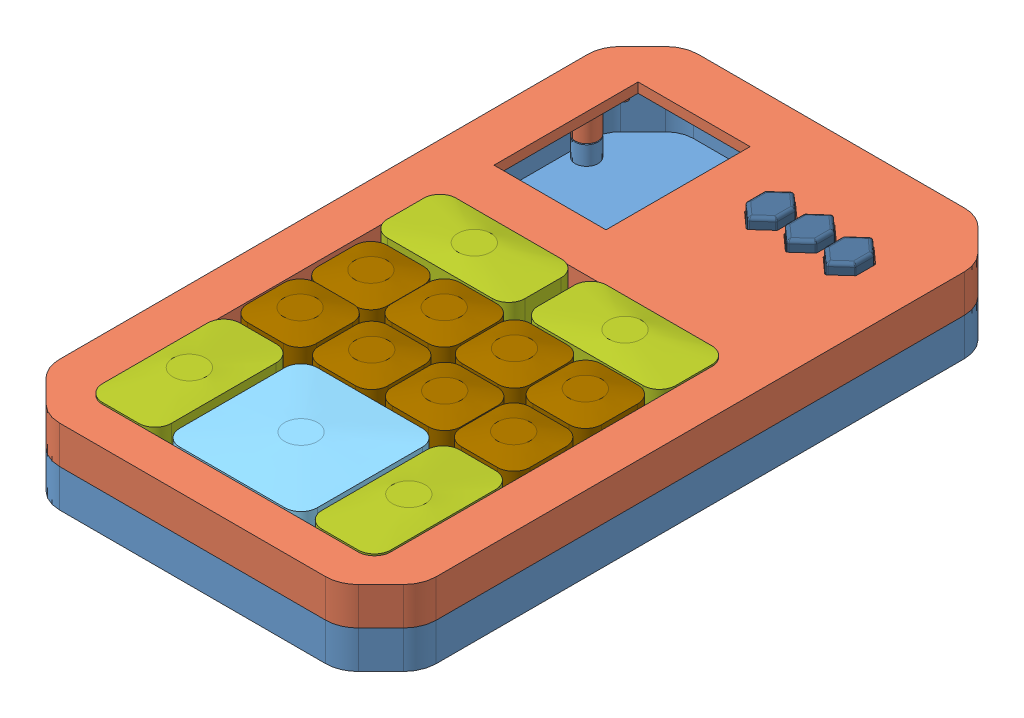
SolidWorks assembly assembly final, configuration Default. Lengths in mm.
Overall size (115 26 195).
46 component instances, 11 part files, 40 mates.
Components (placement in the parent):
- Lower Part-1: Lower Part [Default] at origin size (115 14.5 195)
- PCB board-1: PCB board [Default] at (57.5 10.5 83.7721) size (88 7.5 175) (hidden)
- Upper Part-1: Upper Part [Default] at (0 3 0) size (115 15.5 195)
- batterycap-1: batterycap [Default] at (53.4 1.5 23.6721) x (-1 0 0) z (0 0 1) size (50.2 3 48.69)
- RED-1: RED [Default] at (77.2998 15.5 130.5721) size (42 9.51 42)
  - red lower-1: red lower [Default] at origin size (38.4 6.5 38.4)
  - red upper-1: red upper [Default] at (-40.2 8 40.2) x (1 0 0) z (0 0 -1) size (42 9.51 42)
- Blue-1: Blue [Default] at (99.7 15.5 130.5721) size (21 9.51 42)
  - blue lower-1: blue lower [Default] at origin size (17.4 6.5 38.4)
  - blue upper-1: blue upper [Default] at (1.8 0 -1.8) x (0 0 1) z (-1 0 0) size (42 9.51 21)
- Yellow-1: Yellow [Default] at (33.7262 15.5 108.2986) size (21 9.5 21)
  - yellow lower-1: yellow lower [Default] at origin size (17.4 6.5 17.4)
  - yellow upper-1: yellow upper [Default] at (-19.2 0 -1.8) size (21 9.5 21)
- switch-1: switch [Default] at (94.5 26 26.2721) x (1 0 0) z (0 -1 0) size (9.4 17.88 7.5)
- switch-2: switch [Default] at (82.5 26 11.2721) x (-1 0 0) z (0 -1 0) size (9.4 17.88 7.5)
- switch-3: switch [Default] at (70.5 26 11.2721) x (-1 0 0) z (0 -1 0) size (9.4 17.88 7.5)
- Yellow-2: Yellow [Default] at (33.7049 14.5873 86.656) size (21 9.5 21)
  - yellow lower-1: yellow lower [Default] at origin size (17.4 6.5 17.4)
  - yellow upper-1: yellow upper [Default] at (-19.2 0 -1.8) size (21 9.5 21)
- Blue-2: Blue [Default] at (32.7 15.5 130.5721) size (21 9.51 42)
  - blue lower-1: blue lower [Default] at origin size (17.4 6.5 38.4)
  - blue upper-1: blue upper [Default] at (1.8 0 -1.8) x (0 0 1) z (-1 0 0) size (42 9.51 21)
- Blue-3: Blue [Default] at (15.3 15.5 64.5721) x (0 0 -1) z (1 0 0) size (21 9.51 42)
  - blue lower-1: blue lower [Default] at origin size (17.4 6.5 38.4)
  - blue upper-1: blue upper [Default] at (1.8 0 -1.8) x (0 0 1) z (-1 0 0) size (42 9.51 21)
- Blue-4: Blue [Default] at (99.7 15.5 81.9721) x (0 0 1) z (-1 0 0) size (21 9.51 42)
  - blue lower-1: blue lower [Default] at origin size (17.4 6.5 38.4)
  - blue upper-1: blue upper [Default] at (1.8 0 -1.8) x (0 0 1) z (-1 0 0) size (42 9.51 21)
- Yellow-3: Yellow [Default] at (55.8234 15.5 108.5259) size (21 9.5 21)
  - yellow lower-1: yellow lower [Default] at origin size (17.4 6.5 17.4)
  - yellow upper-1: yellow upper [Default] at (-19.2 0 -1.8) size (21 9.5 21)
- Yellow-4: Yellow [Default] at (99.0982 15.5 108.4626) size (21 9.5 21)
  - yellow lower-1: yellow lower [Default] at origin size (17.4 6.5 17.4)
  - yellow upper-1: yellow upper [Default] at (-19.2 0 -1.8) size (21 9.5 21)
- Yellow-5: Yellow [Default] at (77.8154 15.5 108.2429) size (21 9.5 21)
  - yellow lower-1: yellow lower [Default] at origin size (17.4 6.5 17.4)
  - yellow upper-1: yellow upper [Default] at (-19.2 0 -1.8) size (21 9.5 21)
- Yellow-6: Yellow [Default] at (98.7309 15.5 86.2112) size (21 9.5 21)
  - yellow lower-1: yellow lower [Default] at origin size (17.4 6.5 17.4)
  - yellow upper-1: yellow upper [Default] at (-19.2 0 -1.8) size (21 9.5 21)
- Yellow-7: Yellow [Default] at (55.6875 15.5 86.2617) size (21 9.5 21)
  - yellow lower-1: yellow lower [Default] at origin size (17.4 6.5 17.4)
  - yellow upper-1: yellow upper [Default] at (-19.2 0 -1.8) size (21 9.5 21)
- Yellow-8: Yellow [Default] at (77.2572 15.5 86.3679) size (21 9.5 21)
  - yellow lower-1: yellow lower [Default] at origin size (17.4 6.5 17.4)
  - yellow upper-1: yellow upper [Default] at (-19.2 0 -1.8) size (21 9.5 21)
Mates (geometry in assembly coordinates):
- Coincident1: coincident aligned: plane of Lower Part-1 through (102.2721 20 182.2721) normal (0 0 1); plane of Upper Part-1 through (102.2721 23 182.2721) normal (0 0 1)
- Coincident2: coincident aligned: plane of Lower Part-1 through (115 20 0) normal (1 0 0); plane of Upper Part-1 through (115 23 0) normal (1 0 0)
- Coincident3: coincident anti-aligned: plane of Lower Part-1 through (105 11.5 4.1421) normal (0 1 0); plane of Upper Part-1 through (98.1299 11.5 -2.7279) normal (0 -1 0)
- Coincident4: coincident aligned: plane of Lower Part-1 through (0 0 0) normal (1 0 0)
- Coincident5: coincident aligned: plane of Lower Part-1 through (0 0 0) normal (0 1 0)
- Coincident6: coincident aligned: plane of Lower Part-1 through (0 0 0) normal (0 0 1)
- Coincident7: coincident anti-aligned: plane of Lower Part-1 through (0 10.5 0) normal (0 1 0); plane of PCB board-1 through (57.5 10.5 83.7721) normal (0 -1 0)
- Width1: width aligned: plane of Lower Part-1 through (13 12.5 59.7721) normal (1 0 0); plane of Lower Part-1 through (102 12.5 171.2721) normal (-1 0 0); plane of PCB board-1 through (101.5 12 -3.7279) normal (1 0 0); plane of PCB board-1 through (13.5 12 -3.7279) normal (-1 0 0)
- Width2: width aligned: plane of PCB board-1 through (101.5 10.5 22.2721) normal (0 0 1); plane of PCB board-1 through (101.5 10.5 61.2721) normal (0 0 -1); plane of Lower Part-1 through (103 13 60.7721) normal (0 0 1); plane of Lower Part-1 through (103 13 22.7721) normal (0 0 -1)
- Width3: width aligned: plane of Lower Part-1 through (104 1.5 60.2721) normal (-1 0 0); plane of Lower Part-1 through (53 1.5 60.2721) normal (1 0 0); plane of batterycap-1 through (53.4 0 23.6721) normal (-1 0 0); plane of batterycap-1 through (103.6 0 23.6721) normal (1 0 0)
- Width4: width anti-aligned: plane of Lower Part-1 through (104 1.5 23.2721) normal (0 0 1); plane of Lower Part-1 through (104 1.5 60.2721) normal (0 0 -1); plane of batterycap-1 through (53.4 0 23.6721) normal (0 0 -1); plane of batterycap-1 through (53.4 0 59.8721) normal (0 0 1)
- Coincident8: coincident anti-aligned: plane of Lower Part-1 through (0 1.5 0) normal (0 -1 0); plane of batterycap-1 through (53.4 1.5 23.6721) normal (0 1 0)
- Coincident9: coincident anti-aligned: plane of Upper Part-1 through (18.5 15.5 165.7721) normal (0 1 0); plane of RED-1/red lower-1 through (77.2998 15.5 130.5721) normal (0 -1 0)
- Coincident10: coincident anti-aligned: plane of Upper Part-1 through (18.5 15.5 165.7721) normal (0 1 0); plane of Blue-1/blue lower-1 through (99.7 15.5 130.5721) normal (0 -1 0)
- Coincident12: coincident anti-aligned: plane of switch-1 through (94.5 19.5 26.2721) normal (0 1 0); plane of Upper Part-1 through (70.5 19.5 25.5994) normal (0 -1 0)
- Width5: width anti-aligned: plane of Upper Part-1 through (99.5 2.999 21.7721) normal (-1 0 0); plane of Upper Part-1 through (89.5 2.999 15.7721) normal (1 0 0); plane of switch-1 through (99.2 18.5 15.9057) normal (1 0 0); plane of switch-1 through (89.8 18.5 21.6385) normal (-1 0 0)
- Width6: width aligned: plane of switch-1 through (94.5 18.5 25.8685) normal (-0.668965 0 0.743294); plane of switch-1 through (94.5 18.5 11.6757) normal (0.668965 0 -0.743294); plane of Upper Part-1 through (99.5 2.999 15.7721) normal (-0.668965 0 0.743294); plane of Upper Part-1 through (89.5 2.999 21.7721) normal (0.668965 0 -0.743294)
- Coincident13: coincident anti-aligned: plane of Upper Part-1 through (70.5 19.5 25.5994) normal (0 -1 0); plane of switch-2 through (82.5 19.5 11.2721) normal (0 1 0)
- Width7: width anti-aligned: plane of Upper Part-1 through (87.5 2.999 21.7721) normal (-1 0 0); plane of switch-2 through (77.5 2.999 15.7721) normal (1 0 0); plane of Upper Part-1 through (77.8 18.5 21.6385) normal (-1 0 0); plane of switch-2 through (87.2 18.5 15.9057) normal (1 0 0)
- Width8: width aligned: plane of switch-2 through (82.5 18.5 11.6757) normal (0.668965 0 -0.743294); plane of Upper Part-1 through (82.5 18.5 25.8685) normal (-0.668965 0 0.743294); plane of switch-2 through (77.5 2.999 21.7721) normal (0.668965 0 -0.743294); plane of Upper Part-1 through (87.5 2.999 15.7721) normal (-0.668965 0 0.743294)
- Coincident14: coincident anti-aligned: plane of Upper Part-1 through (70.5 19.5 25.5994) normal (0 -1 0); plane of switch-3 through (70.5 19.5 11.2721) normal (0 1 0)
- Width9: width anti-aligned: plane of Upper Part-1 through (65.5 2.999 15.7721) normal (1 0 0); plane of switch-3 through (75.5 2.999 21.7721) normal (-1 0 0); plane of Upper Part-1 through (65.8 18.5 21.6385) normal (-1 0 0); plane of switch-3 through (75.2 18.5 15.9057) normal (1 0 0)
- Width10: width aligned: plane of switch-3 through (70.5 18.5 11.6757) normal (0.668965 0 -0.743294); plane of Upper Part-1 through (70.5 18.5 25.8685) normal (-0.668965 0 0.743294); plane of switch-3 through (65.5 2.999 21.7721) normal (0.668965 0 -0.743294); plane of Upper Part-1 through (75.5 2.999 15.7721) normal (-0.668965 0 0.743294)
- Coincident16: coincident anti-aligned: plane of Upper Part-1 through (18.5 15.5 165.7721) normal (0 1 0); plane of Yellow-1/yellow lower-1 through (33.7262 15.5 108.2986) normal (0 -1 0)
- Coincident17: coincident anti-aligned: plane of Upper Part-1 through (18.5 15.5 170.7721) normal (0 0 -1); plane of RED-1/red upper-1 through (37.0998 15.5 170.7721) normal (0 0 1)
- Concentric1: concentric anti-aligned: cylinder of Upper Part-1 through (96.5 15.5 165.7721) axis (0 1 0) radius 5; cylinder of Blue-1/blue upper-1 through (96.5 23.5 165.7721) axis (0 -1 0) radius 5
- Coincident19: coincident anti-aligned: plane of Upper Part-1 through (18.5 15.5 165.7721) normal (0 1 0); plane of Blue-2/blue lower-1 through (32.7 15.5 130.5721) normal (0 -1 0)
- Concentric2: concentric anti-aligned: cylinder of Upper Part-1 through (18.5 15.5 165.7721) axis (0 1 0) radius 5; cylinder of Blue-2/blue upper-1 through (18.5 23.5 165.7721) axis (0 -1 0) radius 5
- Coincident20: coincident anti-aligned: plane of Upper Part-1 through (18.5 15.5 165.7721) normal (0 1 0); plane of Blue-4/blue lower-1 through (99.7 15.5 81.9721) normal (0 -1 0)
- Coincident21: coincident anti-aligned: plane of Upper Part-1 through (18.5 15.5 165.7721) normal (0 1 0); plane of Blue-3/blue lower-1 through (15.3 15.5 64.5721) normal (0 -1 0)
- Concentric3: concentric anti-aligned: cylinder of Upper Part-1 through (18.5 15.5 67.7721) axis (0 1 0) radius 5; cylinder of Blue-3/blue upper-1 through (18.5 23.5 67.7721) axis (0 -1 0) radius 5
- Concentric4: concentric anti-aligned: cylinder of Upper Part-1 through (96.5 15.5 67.7721) axis (0 1 0) radius 5; cylinder of Blue-4/blue upper-1 through (96.5 23.5 67.7721) axis (0 -1 0) radius 5
- Coincident22: coincident anti-aligned: plane of Upper Part-1 through (96.5 15.5 62.7721) normal (0 0 1); plane of Blue-3/blue upper-1 through (13.5 23.5 62.7721) normal (0 0 -1)
- Parallel1: parallel aligned: plane of Blue-3/blue upper-1 through (55.5 23.5 83.7721) normal (0 0 1); plane of Blue-4/blue upper-1 through (101.5 23.5 83.7721) normal (0 0 1)
- Coincident23: coincident anti-aligned: plane of Upper Part-1 through (18.5 15.5 165.7721) normal (0 1 0); plane of Yellow-3/yellow lower-1 through (55.8234 15.5 108.5259) normal (0 -1 0)
- Coincident24: coincident anti-aligned: plane of Upper Part-1 through (18.5 15.5 165.7721) normal (0 1 0); plane of Yellow-4/yellow lower-1 through (99.0982 15.5 108.4626) normal (0 -1 0)
- Coincident25: coincident anti-aligned: plane of Upper Part-1 through (18.5 15.5 165.7721) normal (0 1 0); plane of Yellow-5/yellow lower-1 through (77.8154 15.5 108.2429) normal (0 -1 0)
- Coincident26: coincident anti-aligned: plane of Upper Part-1 through (18.5 15.5 165.7721) normal (0 1 0); plane of Yellow-6/yellow lower-1 through (98.7309 15.5 86.2112) normal (0 -1 0)
- Coincident27: coincident anti-aligned: plane of Upper Part-1 through (18.5 15.5 165.7721) normal (0 1 0); plane of Yellow-7/yellow lower-1 through (55.6875 15.5 86.2617) normal (0 -1 0)
- Coincident28: coincident anti-aligned: plane of Upper Part-1 through (18.5 15.5 165.7721) normal (0 1 0); plane of Yellow-8/yellow lower-1 through (77.2572 15.5 86.3679) normal (0 -1 0)
